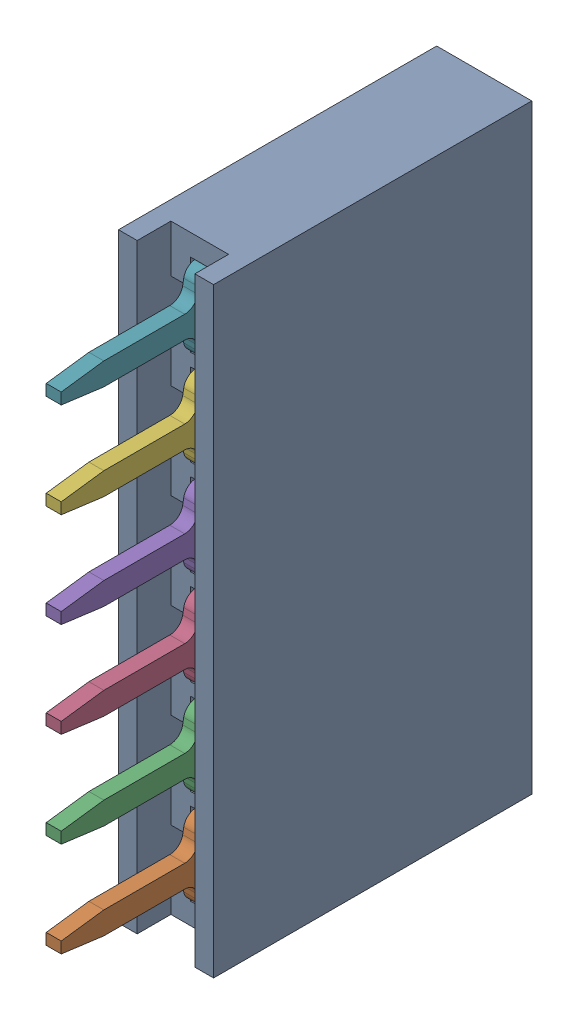
SolidWorks assembly H4_1.step, configuration Default. Lengths in mm.
Overall size (2.54 16.04 11.5).
8 component instances, 2 part files, 0 mates.
Components (placement in the parent):
- DS1023-1x6SF11_1.step-11: DS1023-1x6SF11_1.step [Default] at (465.8362 321.818 -1.647) x (0 1 0) z (0 0 -1) size (16.04 2.54 11.5)
  - body_3.step-32: body_3.step [Default] at origin size (16.04 2.54 8.5)
  - contact_1.step-195: contact_1.step [Default] at origin size (2.3 0.4 9)
  - contact_1.step-196: contact_1.step [Default] at (2.54 0 0) size (2.3 0.4 9)
  - contact_1.step-199: contact_1.step [Default] at (5.08 0 0) size (2.3 0.4 9)
  - contact_1.step-200: contact_1.step [Default] at (7.62 0 0) size (2.3 0.4 9)
  - contact_1.step-201: contact_1.step [Default] at (10.16 0 0) size (2.3 0.4 9)
  - contact_1.step-202: contact_1.step [Default] at (12.7 0 0) size (2.3 0.4 9)
